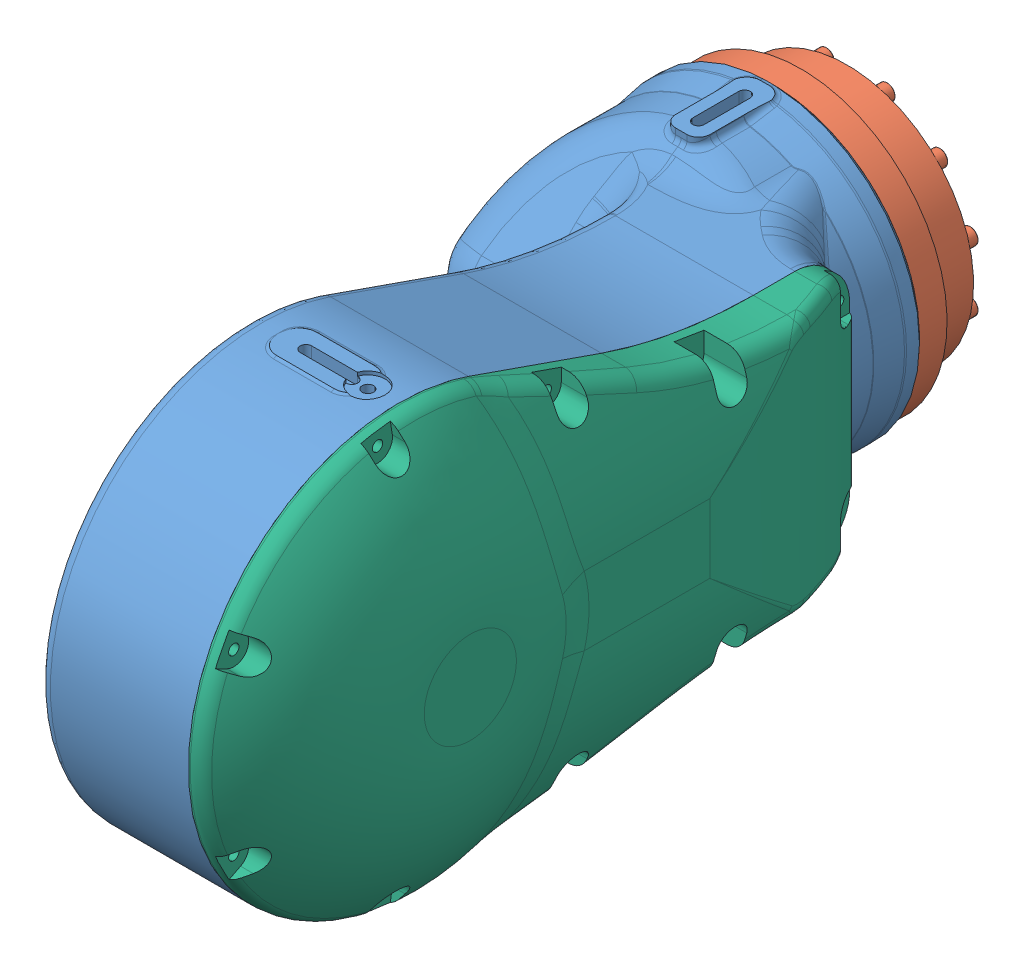
SolidWorks assembly ASM-U__ASM, configuration Valor predeterminado. Lengths in mm.
Overall size (187.2 183.56 363.9).
6 component instances, 6 part files, 0 mates.
Components (placement in the parent):
- CASING_-1: CASING_ [Valor predeterminado] x (-1 0 0) z (0 0 -1) size (139.7 183.56 320.5)
- AC25_-1: AC25_ [Valor predeterminado] at (0 0 -229) x (-0.707107 0.707107 0) z (0.707107 0.707107 0) size (127 90.45 127)
- 0411591_1_-1: 0411591_1_ [Valor predeterminado] at (0 0 -262.6) x (0.707107 -0.707107 0) z (0 0 -1) size (55 55 5.4)
- 0411563_1_-1: 0411563_1_ [Valor predeterminado] at (0 0 -182.4) x (0 0 -1) z (0.707107 0.707107 0) size (90 55 51)
- 0411583_1_-1: 0411583_1_ [Valor predeterminado] at (89.6614 0 0) x (-1 0 0) z (0 -1 0) size (9 90 90)
- L-KABA1_-1: L-KABA1_ [Valor predeterminado] at (66.4 0 0) x (0 1 0) z (1 0 0) size (183 284.37 31.21)
